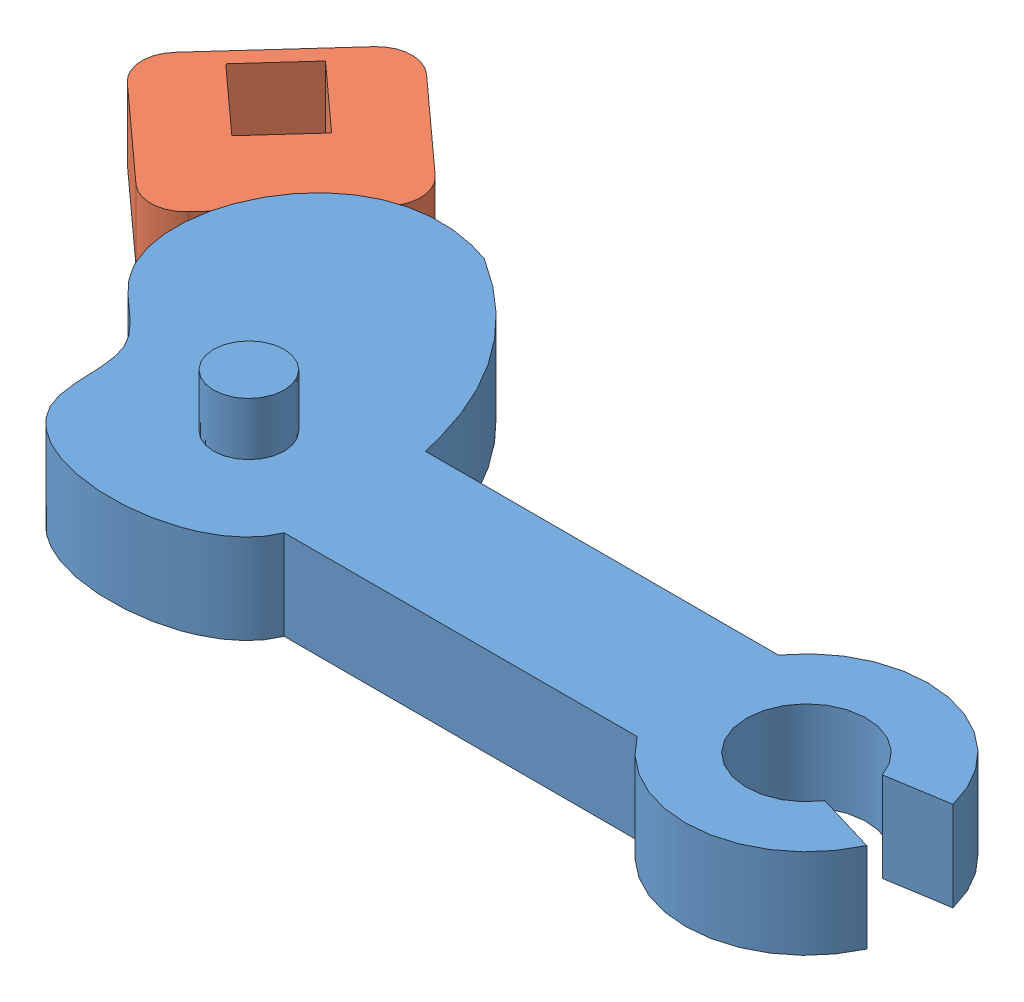
SolidWorks assembly Assem1, configuration Default. Lengths in mm.
Overall size (32.68 6.04 18.09).
2 component instances, 2 part files, 3 mates.
Components (placement in the parent):
- toyarm2-1: toyarm2 [Default] at (4.585 11.8947 23.0446) size (25.43 5.54 11.91)
- toyarm1-1: toyarm1 [Default] at (1.5648 9.8947 21.2223) x (-0.74089 0 -0.671626) z (0.671626 0 -0.74089) size (15.54 2 6)
Mates (geometry in assembly coordinates):
- Concentric1: concentric: cylinder of toyarm2-1 through (-0.2874 10.3947 19.5433) axis (0 1 0) radius 1; cylinder of toyarm1-1 through (-0.2874 11.8947 19.5433) axis (0 -1 0) radius 1
- Concentric2: concentric: cylinder of toyarm2-1 through (-0.2874 10.3947 19.5433) axis (0 1 0) radius 1; cylinder of toyarm1-1 through (-0.2874 11.8947 19.5433) axis (0 -1 0) radius 1
- Coincident1: coincident: plane of toyarm2-1 through (4.585 11.8947 23.0446) normal (0 -1 0); plane of toyarm1-1 through (1.5648 11.8947 21.2223) normal (0 1 0)
